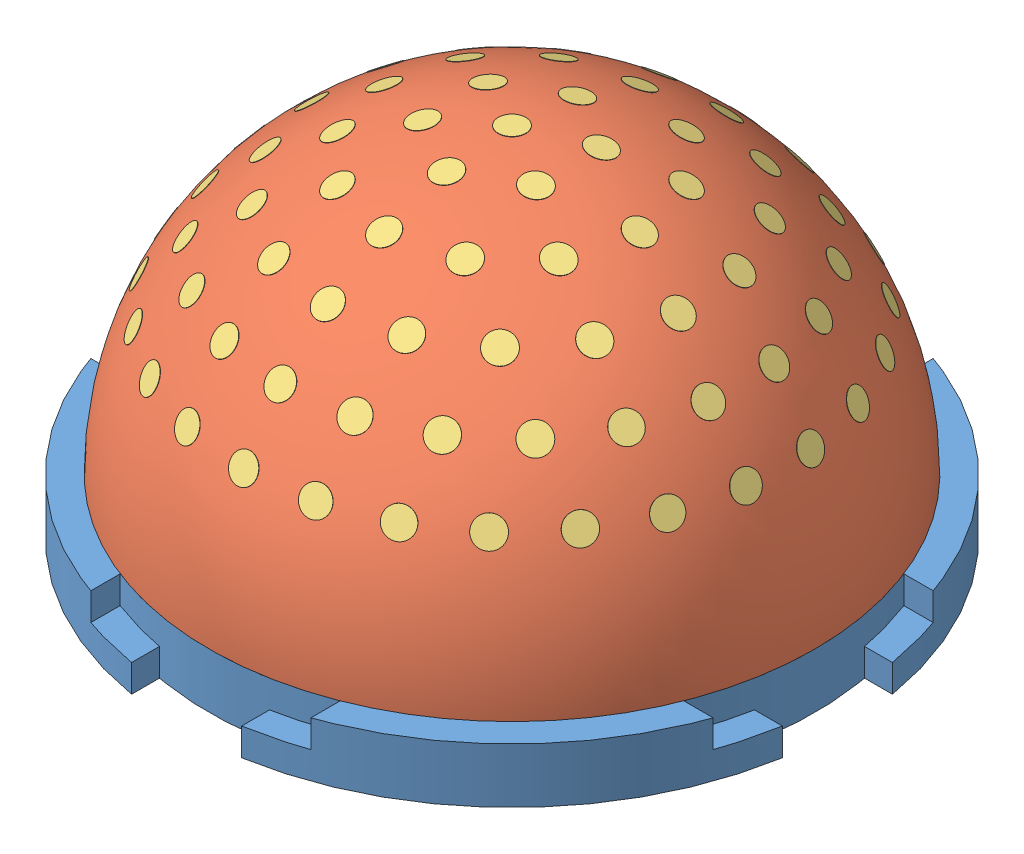
SolidWorks assembly tactile_dome_inner, configuration Default. Lengths in mm.
Overall size (23.66 14 23.66).
3 component instances, 3 part files, 3 mates.
Components (placement in the parent):
- dome_inner_rigidframe-1: dome_inner_rigidframe [Default] at origin size (23.66 3 23.66)
- dome_inner_gel-1: dome_inner_gel [Default] at origin size (22 10.99 22)
- dome_inner_markers-1: dome_inner_markers [Default] at origin size (19.94 6.6 19.91)
Mates (geometry in assembly coordinates):
- Coincident1: coordinate: point of dome_inner_rigidframe-1
- Coincident2: coordinate: unknown of dome_inner_gel-1
- Coincident3: coordinate: unknown of dome_inner_markers-1
